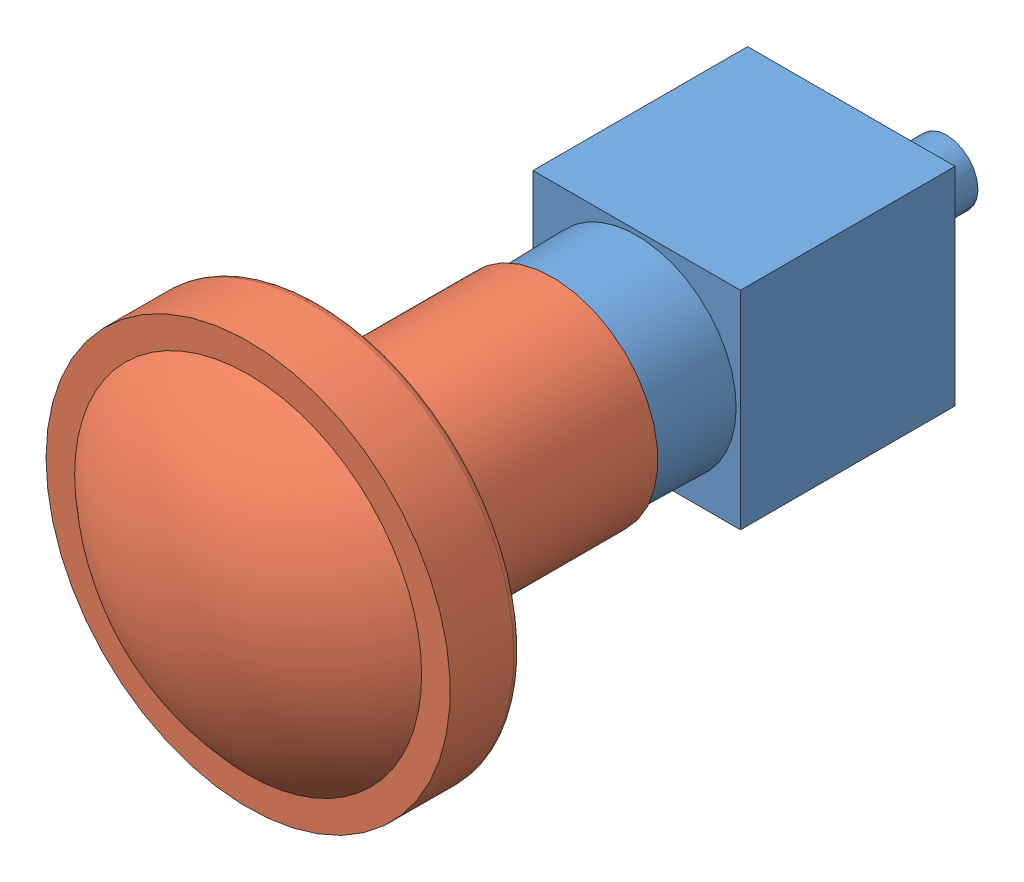
SolidWorks assembly blackfly_fisheye, configuration Cables. Lengths in mm.
Overall size (56.5 56.5 128.3).
2 component instances, 2 part files, 6 mates.
Components (placement in the parent):
- BFS-U3-31S4-1: BFS-U3-31S4 [Default] at (0 14.5 0)
- fisheye_lens-1: fisheye_lens [Default] at (0 14.5 11.8) x (-1 0 0) z (0 0 -1)
Mates (geometry in assembly coordinates):
- Coincident1: coincident aligned: plane of BFS-U3-31S4-1 through (0 14.5 0) normal (1 0 0); plane of assembly through (0 0 0) normal (1 0 0)
- Coincident2: coincident aligned: plane of BFS-U3-31S4-1 through (0 14.5 0) normal (0 0 1); plane of assembly through (0 0 0) normal (0 0 1)
- Coincident3: coincident anti-aligned: plane of BFS-U3-31S4-1 through (-14.5 0 -30) normal (0 -1 0); plane of assembly through (0 0 0) normal (0 1 0)
- Coincident4: coincident anti-aligned: plane of BFS-U3-31S4-1 through (0 14.5 11.8) normal (0 0 1); plane of fisheye_lens-1 through (0 14.5 11.8) normal (0 0 -1)
- Coincident5: coincident anti-aligned: plane of fisheye_lens-1 through (0 14.5 11.8) normal (-1 0 0); plane of assembly through (0 0 0) normal (1 0 0)
- Coincident6: coincident aligned: plane of BFS-U3-31S4-1 through (0 14.5 0) normal (0 1 0); plane of fisheye_lens-1 through (0 14.5 11.8) normal (0 1 0)
